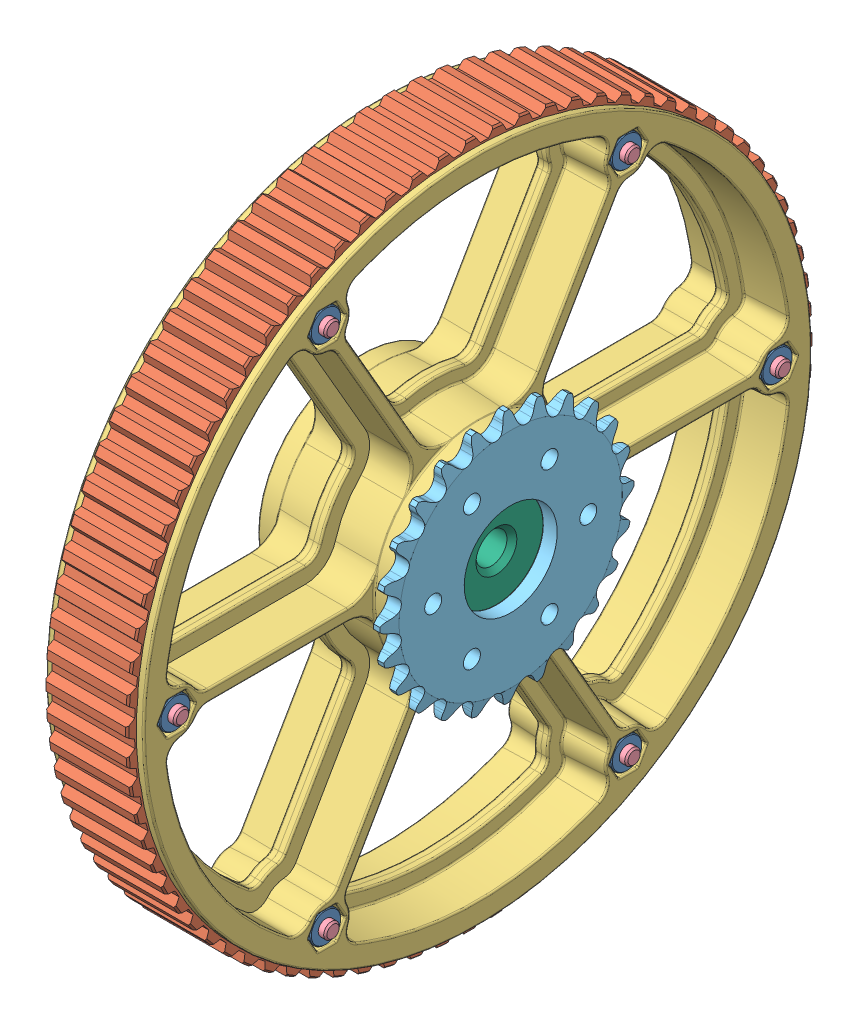
SolidWorks assembly Wheel Drive Free, configuration Default. Lengths in mm.
Overall size (45.93 234.45 234.45).
19 component instances, 6 part files, 9 mates.
Components (placement in the parent):
- 8PlactionRough-1: 8PlactionRough [Default] at origin size (41.66 234.45 234.45)
  - 10-32_nylock_nut-1: 10-32_nylock_nut [Default] at (125.0283 -70.4661 166.4862) x (0 0.793594 -0.608447) z (-1 0 0) size (11.98 11.69 7.5)
  - 10-32_nylock_nut-2: 10-32_nylock_nut [Default] at (125.0283 179.4143 -22.2176) x (0 -0.923728 -0.383049) z (-1 0 0) size (11.98 11.69 7.5)
  - 10-32_nylock_nut-3: 10-32_nylock_nut [Default] at (125.0283 70.4661 -166.4862) x (0 -0.793594 0.608447) z (-1 0 0) size (11.98 11.69 7.5)
  - 10-32_nylock_nut-4: 10-32_nylock_nut [Default] at (125.0283 -108.9482 -144.2686) x (0 0.130134 0.991496) z (-1 0 0) size (11.98 11.69 7.5)
  - 10-32_nylock_nut-5: 10-32_nylock_nut [Default] at (125.0283 -179.4143 22.2176) x (0 0.923728 0.383049) z (-1 0 0) size (11.98 11.69 7.5)
  - 10-32_nylock_nut-6: 10-32_nylock_nut [Default] at (125.0283 108.9482 144.2686) x (0 -0.130134 -0.991496) z (-1 0 0) size (11.98 11.69 7.5)
  - 8RoughTread-1: 8RoughTread [Default] at (8.128 0 0) x (0 -0.992815 0.119662) z (1 0 0) size (210.74 210.74 25.4)
  - 8MW_d01_v2-1: 8MW_d01_v2 [Default] at origin size (22.87 205.23 205.23)
  - 8MW_d01_v2-2: 8MW_d01_v2 [Default] at (41.656 0 0) x (-1 0 0) z (0 0 -1) size (22.87 205.23 205.23)
  - 10-32x1000_shcs-1: 10-32x1000_shcs [Default] at (7.4168 0 92.456) x (0 -0.961068 -0.276312) z (0 0.276312 -0.961068) size (7.82 30.18 7.82)
  - 10-32x1000_shcs-2: 10-32x1000_shcs [Default] at (7.4168 80.0692 -46.228) x (0 0.241241 0.970465) z (0 -0.970465 0.241241) size (7.82 30.18 7.82)
  - 10-32x1000_shcs-3: 10-32x1000_shcs [Default] at (7.4168 0 -92.456) x (0 0.961068 0.276312) z (0 -0.276312 0.961068) size (7.82 30.18 7.82)
  - 10-32x1000_shcs-4: 10-32x1000_shcs [Default] at (7.4168 -80.0692 -46.228) x (0 0.719827 -0.694154) z (0 0.694154 0.719827) size (7.82 30.18 7.82)
  - 10-32x1000_shcs-5: 10-32x1000_shcs [Default] at (7.4168 -80.0692 46.228) x (0 -0.241241 -0.970465) z (0 0.970465 -0.241241) size (7.82 30.18 7.82)
  - 10-32x1000_shcs-6: 10-32x1000_shcs [Default] at (7.4168 80.0692 46.228) x (0 -0.719827 0.694154) z (0 -0.694154 -0.719827) size (7.82 30.18 7.82)
- S35-24L Aluminum Sprocket (am-0217)-1: S35-24L Aluminum Sprocket (am-0217) [2299K314] at (43.7896 0 0) x (0 0.5 -0.866025) z (1 0 0) size (77.98 77.98 4.27)
- 3_8 id 1.125 od ball bearing (1614ZZ) (am-0209)-1: 3_8 id 1.125 od ball bearing (1614ZZ) (am-0209) [Default] at (32.004 0 0) x (0 0 -1) z (1 0 0) size (28.57 28.57 9.53)
- 3_8 id 1.125 od ball bearing (1614ZZ) (am-0209)-2: 3_8 id 1.125 od ball bearing (1614ZZ) (am-0209) [Default] at (9.652 0 0) x (0 0 1) z (-1 0 0) size (28.57 28.57 9.53)
Mates (geometry in assembly coordinates):
- Concentric2: concentric aligned: cone of 8PlactionRough-1/8MW_d01_v2-2 through (41.1657 0 0) axis (-1 0 0); cylinder of S35-24L Aluminum Sprocket (am-0217)-1 through (45.9232 0 0) axis (-1 0 0) radius 14.2812
- Concentric3: concentric anti-aligned: cone of 8PlactionRough-1/8MW_d01_v2-2 through (34.8069 20.6222 11.9062) axis (-1 0 0); cylinder of S35-24L Aluminum Sprocket (am-0217)-1 through (41.656 20.6222 11.9062) axis (1 0 0) radius 2.6162
- Coincident1: coincident anti-aligned: plane of 8PlactionRough-1/8MW_d01_v2-2 through (41.656 0 -31.75) normal (1 0 0); plane of S35-24L Aluminum Sprocket (am-0217)-1 through (41.656 -29.6785 -17.1349) normal (-1 0 0)
- Concentric4: concentric aligned: cone of 8PlactionRough-1/8MW_d01_v2-2 through (41.1657 0 0) axis (-1 0 0); cylinder of 3_8 id 1.125 od ball bearing (1614ZZ) (am-0209)-1 through (41.529 0 0) axis (-1 0 0) radius 14.2875
- Coincident2: coincident anti-aligned: plane of 8PlactionRough-1/8MW_d01_v2-2 through (32.004 0 -14.2875) normal (1 0 0); plane of 3_8 id 1.125 od ball bearing (1614ZZ) (am-0209)-1 through (32.004 0 0) normal (-1 0 0)
- Coincident4: coincident anti-aligned: plane of 3_8 id 1.125 od ball bearing (1614ZZ) (am-0209)-1 through (32.004 0 0) normal (0 0 -1); plane of assembly through (0 0 0) normal (0 0 1)
- Concentric51: concentric aligned: cone of 8PlactionRough-1/8MW_d01_v2-1 through (0.4903 0 0) axis (1 0 0); cylinder of 3_8 id 1.125 od ball bearing (1614ZZ) (am-0209)-2 through (0.127 0 0) axis (1 0 0) radius 4.7625
- Coincident5: coincident anti-aligned: plane of 8PlactionRough-1/8MW_d01_v2-1 through (9.652 0 14.2875) normal (-1 0 0); plane of 3_8 id 1.125 od ball bearing (1614ZZ) (am-0209)-2 through (9.652 0 0) normal (1 0 0)
- Coincident6: coincident aligned: plane of 3_8 id 1.125 od ball bearing (1614ZZ) (am-0209)-2 through (9.652 0 0) normal (0 0 1); plane of assembly
